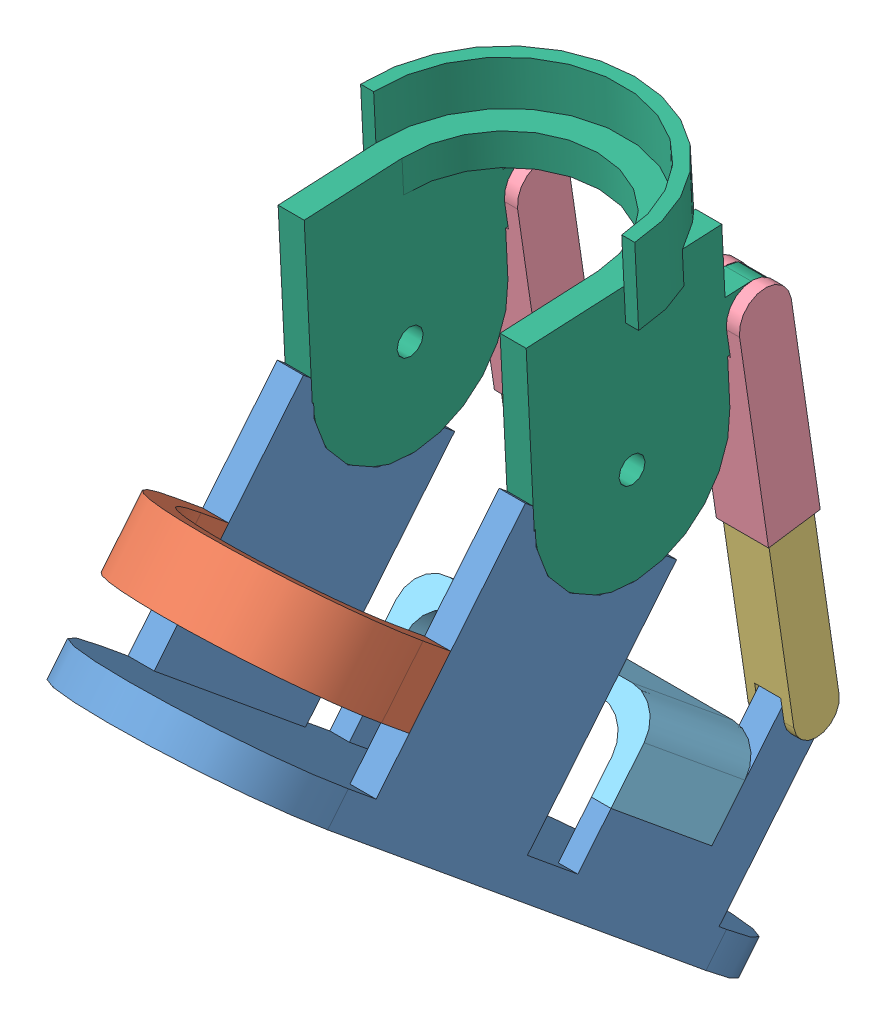
SolidWorks assembly shoes, configuration Default. Lengths in mm.
Overall size (84 234.47 226.66).
8 component instances, 6 part files, 19 mates.
Components (placement in the parent):
- shoes_v0.3-1: shoes_v0.3 [Default] at (91.9397 83.5243 234.6444) x (1 0 0) z (0 0.634939 0.772562) size (76 82 226)
- shoes_back-1: shoes_back [Default] at (91.9397 151.2314 276.0781) x (1 0 0) z (0 0.634939 0.772562) size (76 20 55)
- shoes_pole_b_v0.2-1: shoes_pole_b_v0.2 [Default] at (125.9397 147.1813 154.1222) x (1 0 0) z (0 -0.989372 -0.145404) size (14 14 64)
- shoes_pole_a_v0.2-1: shoes_pole_a_v0.2 [Default] at (125.9397 195.0018 161.1502) x (0 0.145404 -0.989372) z (0 -0.989372 -0.145404) size (16 16 69)
- shoes_top-1: shoes_top [Default] at (91.9397 57.2343 183.765) x (1 0 0) z (0 0.634939 0.772562) size (76 26 40)
- vervel_v0.1-1: vervel_v0.1 [Default] at (91.9397 229.9894 201.7992) x (1 0 0) z (0 0.049537 -0.998772) size (84 94 76)
- shoes_pole_b_v0.2-2: shoes_pole_b_v0.2 [Default] at (57.9397 147.1813 154.1222) x (1 0 0) z (0 -0.989372 -0.145404) size (14 14 64)
- shoes_pole_a_v0.2-2: shoes_pole_a_v0.2 [Default] at (57.9397 195.0018 161.1502) x (0 0.145404 -0.989372) z (0 -0.989372 -0.145404) size (16 16 69)
Mates (geometry in assembly coordinates):
- 重合1: coincident aligned: plane of shoes_v0.3-1 through (129.9397 138.8704 286.2371) normal (1 0 0); plane of shoes_back-1 through (129.9397 166.6826 263.3793) normal (1 0 0)
- 同心1: concentric aligned: cylinder of shoes_v0.3-1 through (125.9397 151.8038 248.4254) axis (0 0.634939 0.772562) radius 2; cylinder of shoes_back-1 through (125.9397 154.3435 251.5156) axis (0 0.634939 0.772562) radius 1.2
- 同心2: concentric aligned: cylinder of shoes_v0.3-1 through (125.9397 151.8038 248.4254) axis (0 0.634939 0.772562) radius 2; cylinder of shoes_back-1 through (125.9397 154.3435 251.5156) axis (0 0.634939 0.772562) radius 1.2
- 重合2: coincident anti-aligned: plane of shoes_v0.3-1 through (129.9397 187.5105 232.0233) normal (0 0.634939 0.772562); plane of shoes_back-1 through (121.9397 159.6983 254.8811) normal (0 -0.634939 -0.772562)
- 重合3: coincident aligned: plane of shoes_v0.3-1 through (129.9397 138.8704 286.2371) normal (1 0 0); plane of vervel_v0.1-1 through (129.9397 151.5737 167.8731) normal (1 0 0)
- 同心3: concentric aligned: cylinder of shoes_v0.3-1 through (53.9397 180.0508 199.3224) axis (1 0 0) radius 30; cylinder of vervel_v0.1-1 through (49.9397 180.0508 199.3224) axis (1 0 0) radius 30
- 重合4: coincident anti-aligned: plane of shoes_v0.3-1 through (91.9397 103.6109 218.1359) normal (0 0.772562 -0.634939); plane of shoes_top-1 through (53.9397 93.4519 205.775) normal (0 -0.772562 0.634939)
- 重合5: coincident aligned: plane of shoes_v0.3-1 through (129.9397 138.8704 286.2371) normal (1 0 0); plane of shoes_top-1 through (129.9397 98.0832 201.9687) normal (1 0 0)
- 重合6: coincident aligned: plane of shoes_v0.3-1 through (129.9397 93.4519 205.775) normal (0 0.634939 0.772562); plane of shoes_top-1 through (70.3236 101.1734 199.4289) normal (0 0.634939 0.772562)
- 同心4: concentric anti-aligned: cylinder of shoes_pole_a_v0.2-1 through (133.9397 203.9062 162.4588) axis (-1 0 0) radius 8; cylinder of vervel_v0.1-1 through (49.9397 203.9062 162.4588) axis (1 0 0) radius 8
- 重合7: coincident anti-aligned: plane of shoes_pole_a_v0.2-1 through (129.9397 210.6579 171.5371) normal (-1 0 0); plane of vervel_v0.1-1 through (129.9397 151.5737 167.8731) normal (1 0 0)
- 同心5: concentric aligned: cylinder of shoes_v0.3-1 through (53.9397 90.7871 145.8342) axis (1 0 0) radius 8; cylinder of shoes_gan_b-1 through (68.9397 90.7871 145.8342) axis (1 0 0) radius 7
- 重合8: coincident anti-aligned: plane of shoes_v0.3-1 through (129.9397 138.8704 286.2371) normal (1 0 0); plane of shoes_gan_b-1 through (129.9397 84.8793 137.8907) normal (-1 0 0)
- 重合9: coincident anti-aligned: plane of shoes_gan_b-1 through (118.9397 82.8436 151.7419) normal (0 -0.145404 0.989372); plane of shoes_pole_a_v0.2-1 through (132.9397 142.5366 160.5148) normal (0 0.145404 -0.989372)
- 同心6: concentric anti-aligned: cylinder of vervel_v0.1-1 through (49.9397 203.9062 162.4588) axis (1 0 0) radius 8; cylinder of shoes_pole_a_v0.2-2 through (65.9397 203.9062 162.4588) axis (-1 0 0) radius 8
- 重合10: coincident anti-aligned: plane of vervel_v0.1-1 through (61.9397 151.5737 167.8731) normal (1 0 0); plane of shoes_pole_a_v0.2-2 through (61.9397 210.6579 171.5371) normal (-1 0 0)
- 同心7: concentric aligned: cylinder of shoes_v0.3-1 through (53.9397 90.7871 145.8342) axis (1 0 0) radius 8; cylinder of shoes_gan_b-2 through (0.9397 90.7871 145.8342) axis (1 0 0) radius 7
- 重合11: coincident anti-aligned: plane of shoes_v0.3-1 through (53.9397 138.8704 286.2371) normal (-1 0 0); plane of shoes_gan_b-2 through (53.9397 84.8793 137.8907) normal (1 0 0)
- 重合12: coincident anti-aligned: plane of shoes_gan_b-2 through (50.9397 82.8436 151.7419) normal (0 -0.145404 0.989372); plane of shoes_pole_a_v0.2-2 through (64.9397 142.5366 160.5148) normal (0 0.145404 -0.989372)
